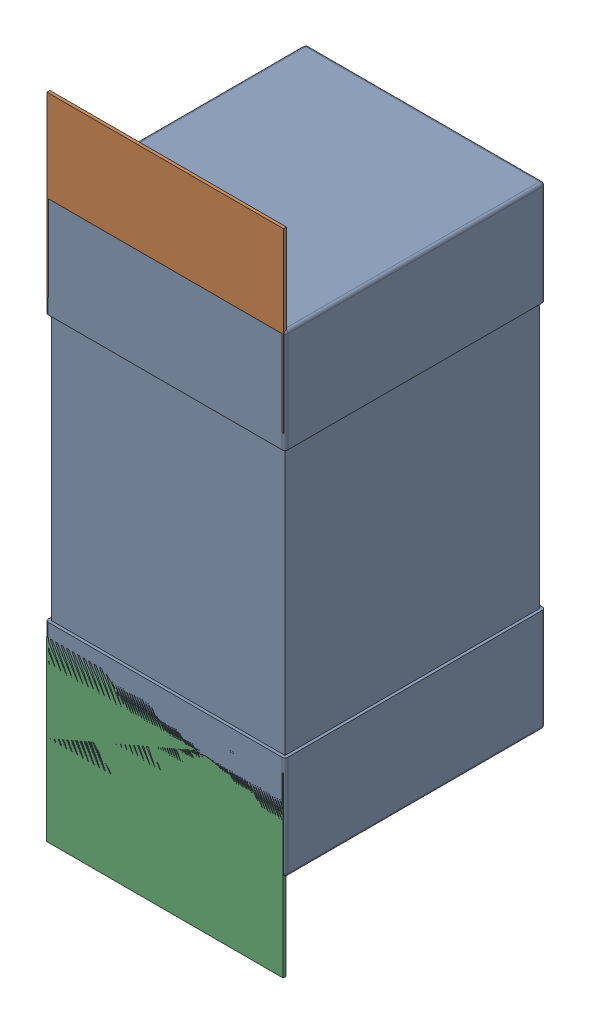
SolidWorks assembly C43, configuration Défaut. Lengths in mm.
Overall size (0.81 2.19 0.88).
5 component instances, 2 part files, 0 mates.
Components (placement in the parent):
- 0603_C-1: 0603_C [Défaut] at (12.0294 -9.4036 -2.0818) x (0 1 0) z (0 0 -1) size (1.6 0.81 0.88)
- 8260087904-1: 8260087904 [Défaut] at (12.0294 -8.1536 -2.0918) size (0.8 0.6 0.01)
  - Extruded_1211-1: Extruded_1211 [Défaut] at origin size (0.8 0.6 0.01)
- 8260087904-2: 8260087904 [Défaut] at (12.0282 -9.7485 -2.0918) size (0.8 0.6 0.01)
  - Extruded_1211-1: Extruded_1211 [Défaut] at origin size (0.8 0.6 0.01)
